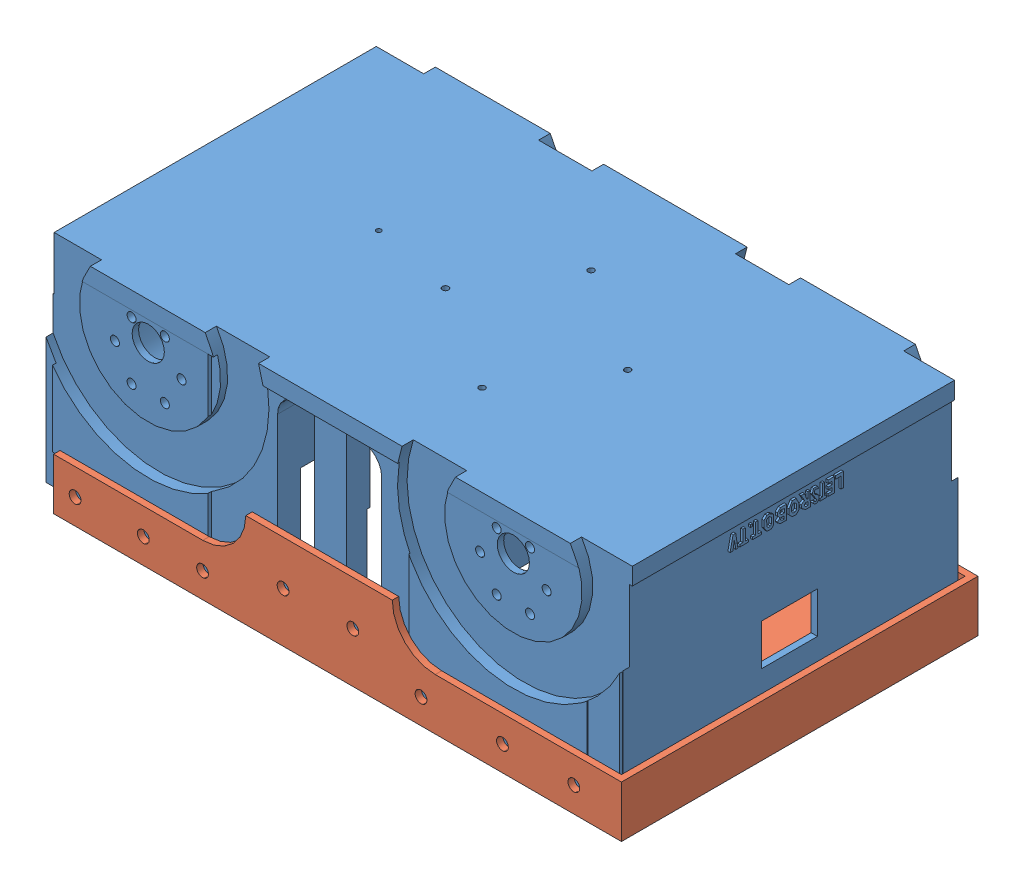
SolidWorks assembly ChassisAndLid, configuration Default. Lengths in mm.
Overall size (296.9 109.84 194.12).
3 component instances, 3 part files, 2 mates.
Components (placement in the parent):
- Chassis3ForSaleRelabeled-1: Chassis3ForSaleRelabeled [Default] at (42.9296 190.2821 237.8976) size (295.52 106.02 194.12)
- Part1^ChassisAndLid-1: Part1^ChassisAndLid [Default] at origin (virtual)
- Lid-1: Lid [Default] at (-9.8563 111.2528 322.8356) size (269.21 44 166)
Mates (geometry in assembly coordinates):
- Distance2: distance = 0.2 mm anti-aligned: plane of Lid-1 through (-6.8563 115.2528 159.835) normal (0 0 1); plane of Chassis3ForSaleRelabeled-1 through (231.3169 214.4528 160.035) normal (0 0 -1)
- Distance3: distance = 0.2 mm anti-aligned: plane of Chassis3ForSaleRelabeled-1 through (42.9296 115.4528 237.8976) normal (0 -1 0); plane of Lid-1 through (-9.8563 115.2528 322.8356) normal (0 1 0)
